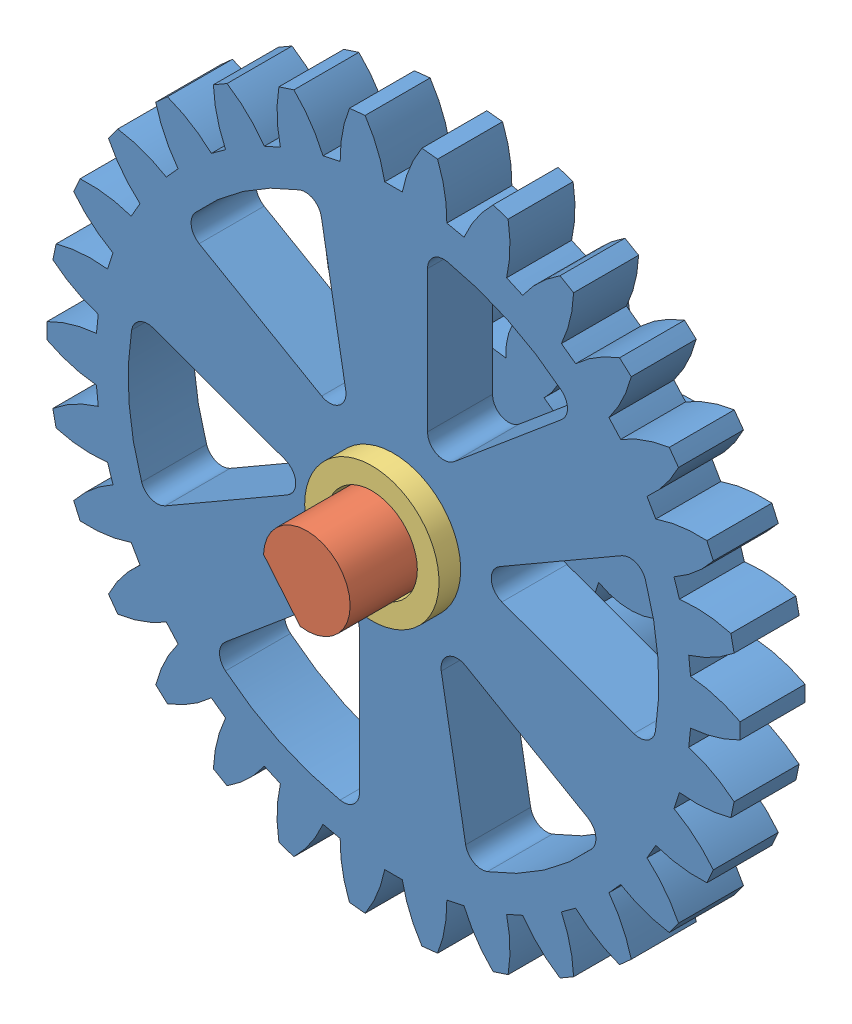
SolidWorks assembly sub 2, configuration Default. Lengths in mm.
Overall size (32 31.89 15).
6 component instances, 3 part files, 10 mates.
Components (placement in the parent):
- root_gear-1: root_gear [30T 1.0Mod] at (18.8313 15.9897 19.7218) size (32 31.89 3)
- root_gear-2: root_gear [10T 1.5Mod] at (18.8313 15.9897 15.7218) x (0.373168 0.927764 0) z (0 0 1) size (18 17.3 3)
- axle-1: axle [15 mm Tall] at (18.8313 15.9897 11.7218) x (-0.639963 0.768406 0) z (0 0 1) size (4 3.5 15)
- spacer-1: spacer [1 mm Tall] at (18.8313 15.9897 14.7218) size (6.2 6.2 1)
- spacer-2: spacer [1 mm Tall] at (18.8313 15.9897 22.7218) size (6.2 6.2 1)
- spacer-3: spacer [1 mm Tall] at (18.8313 15.9897 18.7218) size (6.2 6.2 1)
Mates (geometry in assembly coordinates):
- Concentric1: concentric aligned: cylinder of axle-1 through (18.8313 15.9897 26.7218) axis (0 0 -1) radius 2; cylinder of spacer-2 through (18.8313 15.9897 23.7218) axis (0 0 -1) radius 2.1
- Concentric2: concentric aligned: cylinder of axle-1 through (18.8313 15.9897 26.7218) axis (0 0 -1) radius 2; cylinder of spacer-3 through (18.8313 15.9897 19.7218) axis (0 0 -1) radius 2.1
- Concentric3: concentric aligned: cylinder of axle-1 through (18.8313 15.9897 26.7218) axis (0 0 -1) radius 2; cylinder of spacer-1 through (18.8313 15.9897 15.7218) axis (0 0 -1) radius 2.1
- Concentric4: concentric anti-aligned: cylinder of root_gear-1 through (18.8313 15.9897 19.7218) axis (0 0 1) radius 2; cylinder of axle-1 through (18.8313 15.9897 26.7218) axis (0 0 -1) radius 2
- Concentric5: concentric anti-aligned: cylinder of root_gear-2 through (18.8313 15.9897 15.7218) axis (0 0 1) radius 2; cylinder of axle-1 through (18.8313 15.9897 26.7218) axis (0 0 -1) radius 2
- Coincident1: coincident anti-aligned: plane of root_gear-2 through (18.8313 15.9897 15.7218) normal (0 0 -1); plane of spacer-1 through (18.8313 15.9897 15.7218) normal (0 0 1)
- Coincident2: coincident anti-aligned: plane of root_gear-2 through (18.8313 15.9897 18.7218) normal (0 0 1); plane of spacer-3 through (18.8313 15.9897 18.7218) normal (0 0 -1)
- Coincident4: coincident anti-aligned: plane of root_gear-1 through (18.8313 15.9897 22.7218) normal (0 0 1); plane of spacer-2 through (18.8313 15.9897 22.7218) normal (0 0 -1)
- Coincident5: coincident anti-aligned: plane of root_gear-1 through (18.8313 15.9897 19.7218) normal (0 0 -1); plane of spacer-3 through (18.8313 15.9897 19.7218) normal (0 0 1)
- Distance1: distance = 3 mm aligned: plane of spacer-2 through (18.8313 15.9897 23.7218) normal (0 0 1); plane of axle-1 through (18.8313 15.9897 26.7218) normal (0 0 1)
